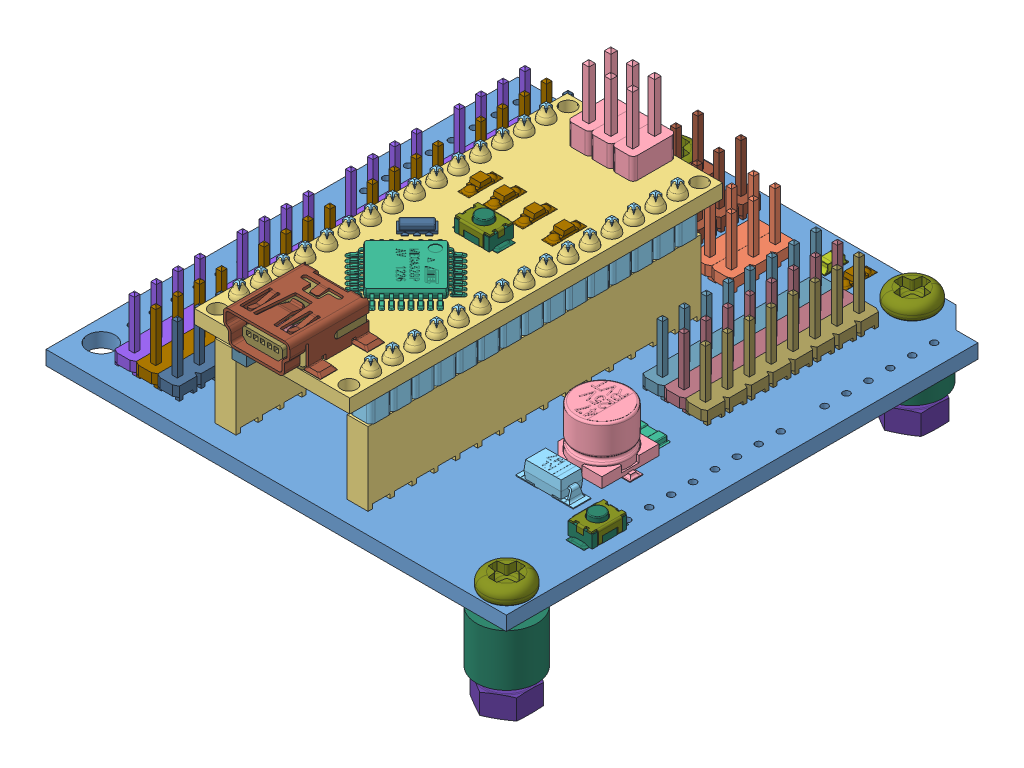
SolidWorks assembly AN, configuration Predeterminado. Lengths in mm.
Overall size (54.3 32.38 59.87).
81 component instances, 35 part files, 24 mates.
Components (placement in the parent):
- Ensamblaje_Shield_NANO-2: Ensamblaje_Shield_NANO [Predeterminado] at (30.2087 16.5393 22.618) size (53.34 23.75 58.91)
  - Shield_Arduino NANO-1: Shield_Arduino NANO [Default] at (28.1337 3.1376 57.2) size (53.34 1.65 57.2)
  - Samtec-TLW-103-01-F-S-1: Samtec-TLW-103-01-F-S [Default] at (7.7639 4.0901 -3.1706) x (0 0 1) z (-1 0 0) size (7.62 10 2.49)
  - Samtec-TLW-103-01-F-S-2: Samtec-TLW-103-01-F-S [Default] at (5.2639 4.0901 -3.1706) x (0 0 1) z (-1 0 0) size (7.62 10 2.49)
  - arduino nano-1: arduino nano [Predeterminado] at (-6.7272 14.1466 6.3422) x (0 0 1) z (-1 0 0) size (45 18.6 18)
    - nano-board-1: nano-board [Predeterminado] at origin size (43.2 4.61 18)
    - 2pin_header__02-1: 2pin_header__02 [Predeterminado] at (-1.143 1.6 -7.62) size (5 11.75 2.54)
    - 2pin_header__02-2: 2pin_header__02 [Predeterminado] at (-1.143 1.6 -5.08) size (5 11.75 2.54)
    - 2pin_header__02-3: 2pin_header__02 [Predeterminado] at (-1.143 1.6 -10.16) size (5 11.75 2.54)
    - 15pin_header__-1: 15pin_header__ [Predeterminado] x (0 0 1) z (1 0 0) size (2.54 11.75 38.1)
    - 15pin_header__-2: 15pin_header__ [Predeterminado] at (0 0 -15.24) x (0 0 1) z (1 0 0) size (2.54 11.75 38.1)
    - atmega328-1: atmega328 [Predeterminado] at (23.85 1.75 -7.62) x (-0.707107 0 0.707107) z (-0.707107 0 -0.707107) size (10 1.1 10)
    - ftdi FT232rl-1: ftdi FT232rl [Predeterminado] at (29.05 0 -7.67) x (0 0 -1) z (-1 0 0) size (9.25 1.9 10.2)
    - smt_resistor222-1: smt_resistor222 [Predeterminado] at (21.86 0 -5.8) x (0 0 -1) z (-1 0 0) size (1.7 0.6 3.8)
    - smt_resistor222-2: smt_resistor222 [Predeterminado] at (21.86 0 -9) x (0 0 -1) z (-1 0 0) size (1.7 0.6 3.8)
    - smt_resistor222-3: smt_resistor222 [Predeterminado] at (36.75 0 -7.6) x (0 0 -1) z (-1 0 0) size (1.7 0.6 3.8)
    - smt_resistor222-4: smt_resistor222 [Predeterminado] at (36.75 0 -12) x (0 0 -1) z (-1 0 0) size (1.7 0.6 3.8)
    - smt_resistor222-5: smt_resistor222 [Predeterminado] at (8.2 0 -2.6) x (0 0 -1) z (-1 0 0) size (1.7 0.6 3.8)
    - led-1: led [Predeterminado] at (10.4 1.6 -2.8) size (4 0.9 1.55)
    - led-2: led [Predeterminado] at (10.4 1.6 -5.55) size (4 0.9 1.55)
    - led-3: led [Predeterminado] at (10.4 1.6 -12.5) size (4 0.9 1.55)
    - led-4: led [Predeterminado] at (10.4 1.6 -9.05) size (4 0.9 1.55)
    - 16mhz crystal - measured-1: 16mhz crystal - measured [Predeterminado] at (18.5113 1.6 -3.5541) x (0.707107 0 0.707107) z (-0.707107 0 0.707107) size (3.4 0.8 2.01)
    - MINIUSB - MEASURED-1: MINIUSB - MEASURED [Predeterminado] at (38.98 1.65 -7.62) x (0 0 1) z (-1 0 0) size (11.03 4.95 10.42)
      - MINIUSBSHELL-1: MINIUSBSHELL [Predeterminado] at origin size (11.03 3.97 9.48)
      - MINIUSBCORE-1: MINIUSBCORE [Predeterminado] at (0 0 6.7) x (-1 0 0) z (0 0 -1) size (7.7 4.5 8.2)
      - MINI USB CONTACT-1: MINI USB CONTACT [Predeterminado] at (-1.6 0 5.7) x (-1 0 0) z (0 0 -1) size (0.53 2.55 9.41)
      - MINI USB CONTACT-2: MINI USB CONTACT [Predeterminado] at (-0.8 0 5.7) x (-1 0 0) z (0 0 -1) size (0.53 2.55 9.41)
      - MINI USB CONTACT-3: MINI USB CONTACT [Predeterminado] at (0 0 5.7) x (-1 0 0) z (0 0 -1) size (0.53 2.55 9.41)
      - MINI USB CONTACT-4: MINI USB CONTACT [Predeterminado] at (0.8 0 5.7) x (-1 0 0) z (0 0 -1) size (0.53 2.55 9.41)
      - MINI USB CONTACT-5: MINI USB CONTACT [Predeterminado] at (1.6 0 5.7) x (-1 0 0) z (0 0 -1) size (0.53 2.55 9.41)
    - cap106C-1: cap106C [Predeterminado] at (37.2 0 -3.3) x (0 0 1) z (1 0 0) size (1.7 1.81 4)
    - cap106C-2: cap106C [Predeterminado] at (7.9 0 -5.6) x (0 0 -1) z (-1 0 0) size (1.7 1.81 4)
    - reset button-1: reset button [Predeterminado] at (15.25 1.6 -8.05) x (0 0 -1) z (1 0 0) size (5.21 2.15 3)
      - reset core-1: reset core [Predeterminado] at origin size (5.21 2.15 2.8)
      - reset shell-1: reset shell [Predeterminado] at (0 1.65 0) x (0 0 1) z (-1 0 0) size (3 1.65 4)
    - nano - reg-1: nano - reg [Predeterminado] at (6.1 0 -10.16) x (0 0 -1) z (-1 0 0) size (6.5 1.69 8.3)
    - NANO DIODE-1: NANO DIODE [Predeterminado] at (11.43 0 -4.2) x (0 0 1) z (1 0 0) size (4.92 1.38 1.7)
    - 189 RESISTOR PACK-1: 189 RESISTOR PACK [Predeterminado] at (15.75 0 -10.85) x (0 0 1) z (1 0 0) size (3.2 0.51 3)
    - 102 RESISTOR PACK-1: 102 RESISTOR PACK [Predeterminado] at (15.75 0 -5.2) x (0 0 1) z (1 0 0) size (3.2 0.51 3)
  - Samtec-SSW-115-01-F-S-3: Samtec-SSW-115-01-F-S [Default] at (8.5128 3.1376 24.1222) size (2.41 11.15 38.61)
  - Samtec-SSW-115-01-F-S-4: Samtec-SSW-115-01-F-S [Default] at (-6.7872 3.1376 24.1222) size (2.41 11.15 38.61)
  - 47uf CAP Dcase-1: 47uf CAP Dcase [Default] at (17.9906 3.1376 24.6048) x (0 0 -1) z (1 0 0) size (6.6 5.81 8)
  - m7 diode-1: m7 diode [Default] at (18.0456 3.1376 30.2824) size (6.66 2.35 2.5)
  - smt_resistor222_a-1: smt_resistor222_a [Default] at (18.3832 3.1376 19.7626) x (0 0 -1) z (1 0 0) size (1.7 0.6 3.8)
  - nano - reg-1: nano - reg [Predeterminado] at (1.246 3.1376 24.0398) x (0 0 1) z (-1 0 0) size (6.5 1.69 8.3)
  - cap106C-1: cap106C [Predeterminado] at (1.2297 3.1376 32.7528) x (0 0 1) z (-1 0 0) size (1.7 1.81 4)
  - smt_resistor222_a-2: smt_resistor222_a [Default] at (1.378 3.1376 29.6673) x (0 0 -1) z (1 0 0) size (1.7 0.6 3.8)
  - smt_resistor222_a-3: smt_resistor222_a [Default] at (1.364 3.1376 18.2634) x (0 0 -1) z (1 0 0) size (1.7 0.6 3.8)
  - cap106C-2: cap106C [Predeterminado] at (1.6627 3.1376 15.2796) x (0 0 1) z (-1 0 0) size (1.7 1.81 4)
  - led-1: led [Predeterminado] at (14.5957 3.1376 -8.0824) x (0 0 -1) z (1 0 0) size (4 0.9 1.55)
  - reset button-1: reset button [Predeterminado] at (25.102 3.1376 32.2333) x (0 0 -1) z (1 0 0) size (5.21 2.15 3)
    - reset core-1: reset core [Predeterminado] at origin size (5.21 2.15 2.8)
    - reset shell-1: reset shell [Predeterminado] at (0 1.65 0) x (0 0 1) z (-1 0 0) size (3 1.65 4)
  - blm21-1: blm21 [Default] at (11.9193 3.1376 -8.0299) x (0 0 -1) z (1 0 0) size (2.76 0.95 1.32)
  - Samtec-TLW-104-01-F-S_N-1: Samtec-TLW-104-01-F-S_N [Default] at (-18.4832 4.0901 38.492) x (0 0 -1) z (1 0 0) size (10.16 10 2.49)
  - Samtec-TLW-104-01-F-S_N-2: Samtec-TLW-104-01-F-S_N [Default] at (-18.4832 4.0901 25.942) x (0 0 -1) z (1 0 0) size (10.16 10 2.49)
  - Samtec-TLW-104-01-F-S_N-3: Samtec-TLW-104-01-F-S_N [Default] at (-18.4832 4.0901 13.392) x (0 0 -1) z (1 0 0) size (10.16 10 2.49)
  - Samtec-TLW-104-01-F-S_N-4: Samtec-TLW-104-01-F-S_N [Default] at (-18.4832 4.0901 0.842) x (0 0 -1) z (1 0 0) size (10.16 10 2.49)
  - Samtec-TLW-104-01-F-S_R-1: Samtec-TLW-104-01-F-S_R [Default] at (-15.994 4.0901 38.492) x (0 0 1) z (-1 0 0) size (10.16 10 2.49)
  - Samtec-TLW-104-01-F-S_R-2: Samtec-TLW-104-01-F-S_R [Default] at (-15.994 4.0901 25.942) x (0 0 1) z (-1 0 0) size (10.16 10 2.49)
  - Samtec-TLW-104-01-F-S_R-3: Samtec-TLW-104-01-F-S_R [Default] at (-15.994 4.0901 13.392) x (0 0 1) z (-1 0 0) size (10.16 10 2.49)
  - Samtec-TLW-104-01-F-S_R-4: Samtec-TLW-104-01-F-S_R [Default] at (-15.994 4.0901 0.842) x (0 0 1) z (-1 0 0) size (10.16 10 2.49)
  - Samtec-TLW-104-01-F-S_B-1: Samtec-TLW-104-01-F-S_B [Default] at (-13.5048 4.0901 38.492) x (0 0 -1) z (1 0 0) size (10.16 10 2.49)
  - Samtec-TLW-104-01-F-S_B-2: Samtec-TLW-104-01-F-S_B [Default] at (-13.5048 4.0901 25.942) x (0 0 -1) z (1 0 0) size (10.16 10 2.49)
  - Samtec-TLW-104-01-F-S_B-3: Samtec-TLW-104-01-F-S_B [Default] at (-13.5048 4.0901 13.392) x (0 0 -1) z (1 0 0) size (10.16 10 2.49)
  - Samtec-TLW-104-01-F-S_B-4: Samtec-TLW-104-01-F-S_B [Default] at (-13.5048 4.0901 0.842) x (0 0 -1) z (1 0 0) size (10.16 10 2.49)
  - Samtec-TLW-104-01-F-S_W-1: Samtec-TLW-104-01-F-S_W [Default] at (-4.0059 4.0901 -4.7024) x (0 0 -1) z (1 0 0) size (10.16 10 2.49)
  - Samtec-TLW-104-01-F-S_W-2: Samtec-TLW-104-01-F-S_W [Default] at (0.9469 4.0901 -4.7452) x (0 0 -1) z (1 0 0) size (10.16 10 2.49)
  - Samtec-TLW-108-01-F-S_B-1: Samtec-TLW-108-01-F-S_B [Default] at (19.5362 4.0901 5.2512) x (0 0 -1) z (1 0 0) size (20.32 10 2.49)
  - Samtec-TLW-108-01-F-S_R-1: Samtec-TLW-108-01-F-S_R [Default] at (17.047 4.0901 5.2512) x (0 0 1) z (-1 0 0) size (20.32 10 2.49)
  - Samtec-TLW-108-01-F-S_N-1: Samtec-TLW-108-01-F-S_N [Default] at (14.5578 4.0901 5.2512) x (0 0 1) z (-1 0 0) size (20.32 10 2.49)
- separador-1: separador [Predeterminado] at (55.8024 18.0269 65.848) x (1 0 0) z (0 -1 0) size (7 7 6)
- M3x10 Philips Screw-1: M3x10 Philips Screw [Predeterminado] at (55.8024 19.6769 65.848) x (1 0 0) z (0 1 0) size (5.3 5.3 11.8)
- M3 Nut-1: M3 Nut [Predeterminado] at (55.8024 12.5269 65.848) x (1 0 0) z (0 1 0) size (6.27 6.27 2.71)
- M3 Nut-2: M3 Nut [Predeterminado] at (50.7224 7.0269 13.778) x (0.999652 0 0.026398) z (0 -1 0) size (6.27 6.27 2.71)
- separador-2: separador [Predeterminado] at (50.7224 18.0269 13.778) x (1 0 0) z (0 -1 0) size (7 7 6)
- M3x10 Philips Screw-2: M3x10 Philips Screw [Predeterminado] at (50.7224 19.6769 13.778) x (1 0 0) z (0 1 0) size (5.3 5.3 11.8)
- M3x10 Philips Screw-3: M3x10 Philips Screw [Predeterminado] at (22.7824 19.6769 13.778) x (1 0 0) z (0 1 0) size (5.3 5.3 11.8)
- separador-3: separador [Predeterminado] at (22.7824 18.0269 13.778) x (1 0 0) z (0 -1 0) size (7 7 6)
- M3 Nut-3: M3 Nut [Predeterminado] at (22.7824 7.0269 13.778) x (1 0 0) z (0 -1 0) size (6.27 6.27 2.71)
Mates (geometry in assembly coordinates):
- Coincidente2: coincident: plane of Ensamblaje_Shield_NANO-2/Shield_Arduino NANO-1 through (58.3424 18.0269 79.818) normal (0 -1 0); plane of ? through (22.7824 18.0269 13.778) normal (0 1 0)
- Coincidente3: coincident: plane of Ensamblaje_Shield_NANO-2/Shield_Arduino NANO-1 through (58.3424 18.0269 79.818) normal (0 -1 0); plane of ? through (55.8024 18.0269 65.848) normal (0 1 0)
- Coincidente4: coincident: plane of Ensamblaje_Shield_NANO-2/Shield_Arduino NANO-1 through (58.3424 18.0269 79.818) normal (0 -1 0); plane of ? through (50.7224 18.0269 13.778) normal (0 1 0)
- Concéntrica2: concentric: circle of Ensamblaje_Shield_NANO-2/Shield_Arduino NANO-1; circle of ?
- Concéntrica3: concentric: circle of Ensamblaje_Shield_NANO-2/Shield_Arduino NANO-1; circle of ?
- Concéntrica4: concentric: circle of Ensamblaje_Shield_NANO-2/Shield_Arduino NANO-1; circle of ?
- Coincidente5: coincident: plane of Ensamblaje_Shield_NANO-2/Shield_Arduino NANO-1 through (58.3424 19.6769 79.818) normal (0 1 0); plane of M3x10 Philips Screw-1 through (55.8024 19.6769 64.248) normal (0 -1 0)
- Concéntrica5: concentric: circle of Ensamblaje_Shield_NANO-2/Shield_Arduino NANO-1; circle of M3x10 Philips Screw-1
- Coincidente6: coincident: plane of Ensamblaje_Shield_NANO-2/Shield_Arduino NANO-1 through (58.3424 18.0269 79.818) normal (0 -1 0); plane of separador-1 through (55.8024 18.0269 65.848) normal (0 1 0)
- Concéntrica6: concentric: circle of Ensamblaje_Shield_NANO-2/Shield_Arduino NANO-1; circle of separador-1
- Distancia1: distance = 1 mm: plane of M3 Nut-1 through (55.8024 11.0269 65.848) normal (0 1 0); plane of separador-1 through (55.8024 12.0269 65.848) normal (0 -1 0)
- Concéntrica7: concentric: circle of separador-1; circle of M3 Nut-1
- Coincidente8: coincident: plane of Ensamblaje_Shield_NANO-2/Shield_Arduino NANO-1 through (58.3424 19.6769 79.818) normal (0 1 0); plane of M3x10 Philips Screw-2 through (50.7224 19.6769 12.178) normal (0 -1 0)
- Coincidente9: coincident: plane of Ensamblaje_Shield_NANO-2/Shield_Arduino NANO-1 through (58.3424 18.0269 79.818) normal (0 -1 0); plane of separador-2 through (50.7224 18.0269 13.778) normal (0 1 0)
- Coincidente10: coincident: plane of Ensamblaje_Shield_NANO-2/Shield_Arduino NANO-1 through (58.3424 19.6769 79.818) normal (0 1 0); plane of M3x10 Philips Screw-3 through (22.7824 19.6769 12.178) normal (0 -1 0)
- Coincidente11: coincident: plane of Ensamblaje_Shield_NANO-2/Shield_Arduino NANO-1 through (58.3424 18.0269 79.818) normal (0 -1 0); plane of separador-3 through (22.7824 18.0269 13.778) normal (0 1 0)
- Concéntrica8: concentric: circle of Ensamblaje_Shield_NANO-2/Shield_Arduino NANO-1; circle of separador-2
- Concéntrica9: concentric: circle of Ensamblaje_Shield_NANO-2/Shield_Arduino NANO-1; circle of M3x10 Philips Screw-2
- Concéntrica10: concentric: circle of Ensamblaje_Shield_NANO-2/Shield_Arduino NANO-1; circle of M3x10 Philips Screw-3
- Concéntrica11: concentric: circle of Ensamblaje_Shield_NANO-2/Shield_Arduino NANO-1; circle of separador-3
- Concéntrica12: concentric: circle of M3 Nut-2; circle of separador-2
- Concéntrica13: concentric: circle of separador-3; circle of M3 Nut-3
- Distancia2: distance = 1 mm: plane of M3 Nut-3 through (22.7824 11.0269 13.778) normal (0 1 0); plane of separador-3 through (22.7824 12.0269 13.778) normal (0 -1 0)
- Distancia3: distance = 1 mm: plane of M3 Nut-2 through (50.7224 11.0269 13.778) normal (0 1 0); plane of separador-2 through (50.7224 12.0269 13.778) normal (0 -1 0)
